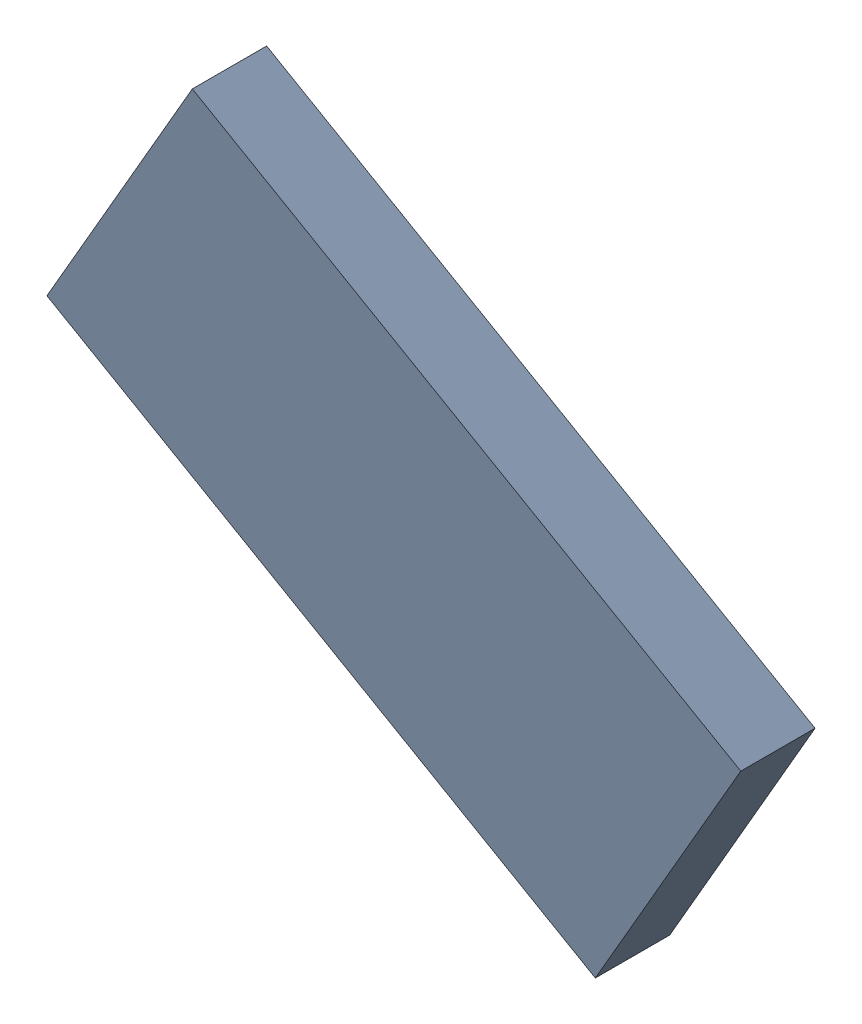
SolidWorks assembly TDA5340_TDA6, configuration Standard. Lengths in mm.
Overall size (10.74 8.8 1.15).
2 component instances, 1 part files, 0 mates.
Components (placement in the parent):
- 885544416-1: 885544416 [Standard] at (-42.5822 26.8379 0.05) size (10.74 8.8 1.15)
  - Extruded_11-1: Extruded_11 [Standard] at origin size (10.74 8.8 1.15)
